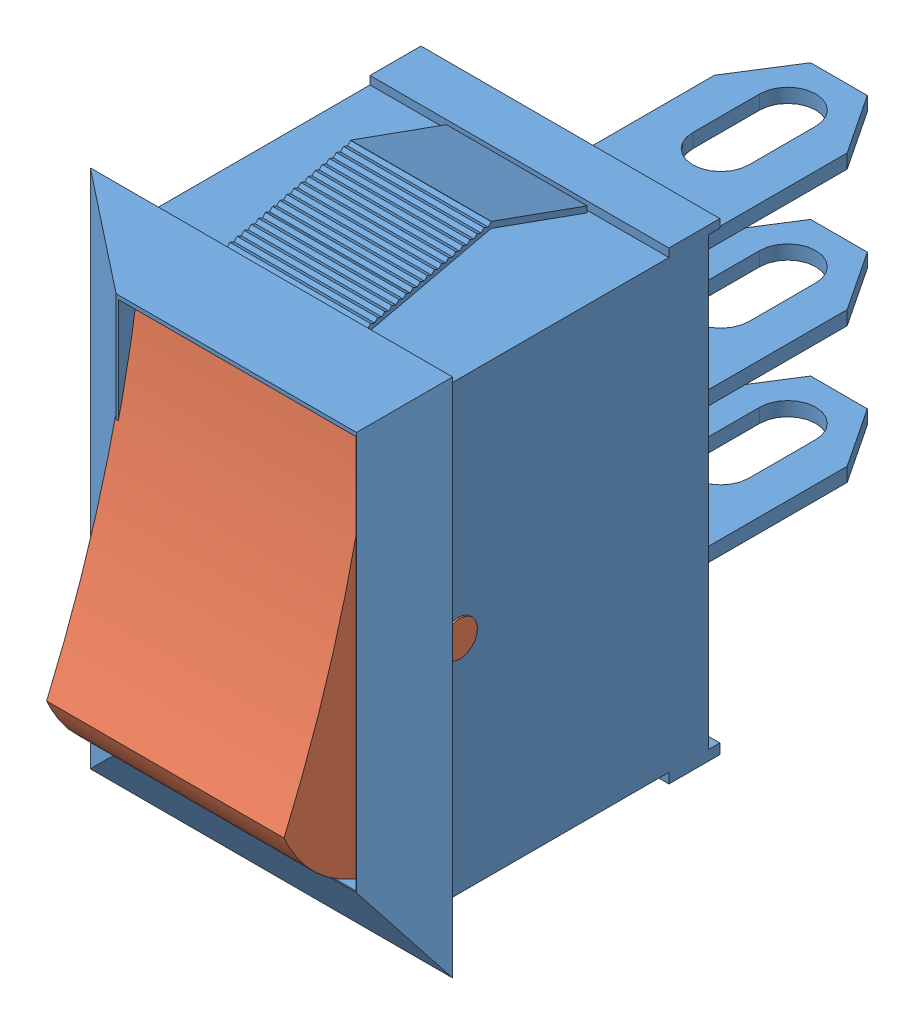
SolidWorks assembly Switch Button, configuration Default. Lengths in mm.
Overall size (10.3 14.93 19.11).
3 component instances, 2 part files, 0 mates.
Components (placement in the parent):
- Switch Button.stp-1: Switch Button.stp [Default] at origin size (10.3 14.93 19.11)
  - Suis.stp-1: Suis.stp [Default] at (0 0 -3.1918) size (10.3 14.93 17.17)
  - Part1.stp-1: Part1.stp [Default] at (-0.0751 0 0) size (8.75 11.18 6.37)
